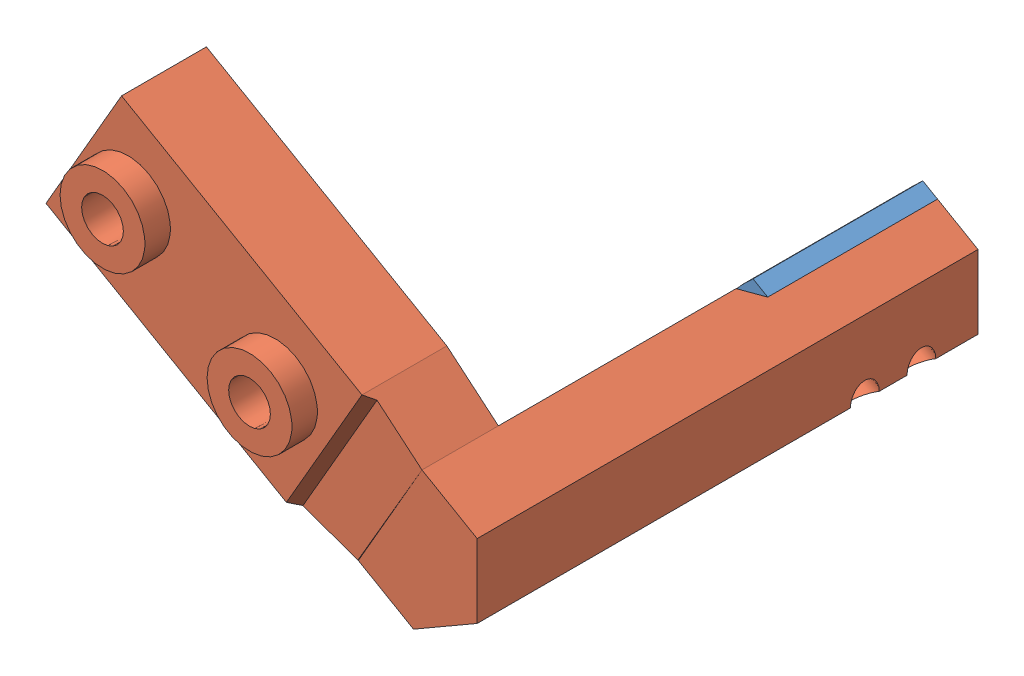
SolidWorks assembly chela, configuration Default. Lengths in mm.
Overall size (49.79 38.22 63).
4 component instances, 3 part files, 7 mates.
Components (placement in the parent):
- Gommino-1: Gommino [Default] at (3.3677 -6.4971 10) size (9.23 13.99 20)
- Asta_chela-1: Asta_chela [Default] at (3.3677 -6.4971 10) size (49.79 38.22 63)
- socket countersunk head screw_iso-2: socket countersunk head screw_iso [ISO 10642 - M3 x 8 - 8N] at (-8.32 0.2508 23.3333) x (0.866025 -0.5 0) z (0.497551 0.861784 0.098852) size (8 5.54 5.54)
- socket countersunk head screw_iso-3: socket countersunk head screw_iso [ISO 10642 - M3 x 8 - 8N] at (-8.32 0.2508 16.6667) x (0.866025 -0.5 0) z (0.240379 0.416349 0.876853) size (8 5.54 5.54)
Mates (geometry in assembly coordinates):
- Coincidente1: coincident anti-aligned: plane of Gommino-1 through (-6.1502 -1.0019 30) normal (0.866025 -0.5 0); plane of Asta_chela-1 through (-6.1502 -1.0019 10) normal (-0.866025 0.5 0)
- Concentrico1: concentric aligned: cylinder of Gommino-1 through (-0.5252 -4.2495 16.6667) axis (-0.866025 0.5 0) radius 1.75; cylinder of Asta_chela-1 through (-6.1502 -1.0019 16.6667) axis (-0.866025 0.5 0) radius 1.7
- Coincidente2: coincident aligned: plane of Gommino-1 through (7.1177 -0.0019 30) normal (0.5 0.866025 0); plane of Asta_chela-1 through (7.1177 -0.0019 70) normal (0.5 0.866025 0)
- Concentrico2: concentric aligned: cylinder of Asta_chela-1 through (-6.1502 -1.0019 23.3333) axis (-0.866025 0.5 0) radius 1.7; cylinder of socket countersunk head screw_iso-2 through (-8.32 0.2508 23.3333) axis (-0.866025 0.5 0) radius 1.5
- Coincidente4: coincident aligned: cone of Gommino-1 through (-6.9257 -0.5542 23.3333) axis (0.866025 -0.5 0); cone of socket countersunk head screw_iso-2 through (-7.809 -0.0442 23.3333) axis (0.866025 -0.5 0)
- Concentrico3: concentric aligned: cylinder of Asta_chela-1 through (-6.1502 -1.0019 16.6667) axis (-0.866025 0.5 0) radius 1.7; cylinder of socket countersunk head screw_iso-3 through (-8.32 0.2508 16.6667) axis (-0.866025 0.5 0) radius 1.5
- Coincidente5: coincident aligned: cone of Gommino-1 through (-6.9257 -0.5542 16.6667) axis (0.866025 -0.5 0); cone of socket countersunk head screw_iso-3 through (-7.809 -0.0442 16.6667) axis (0.866025 -0.5 0)
